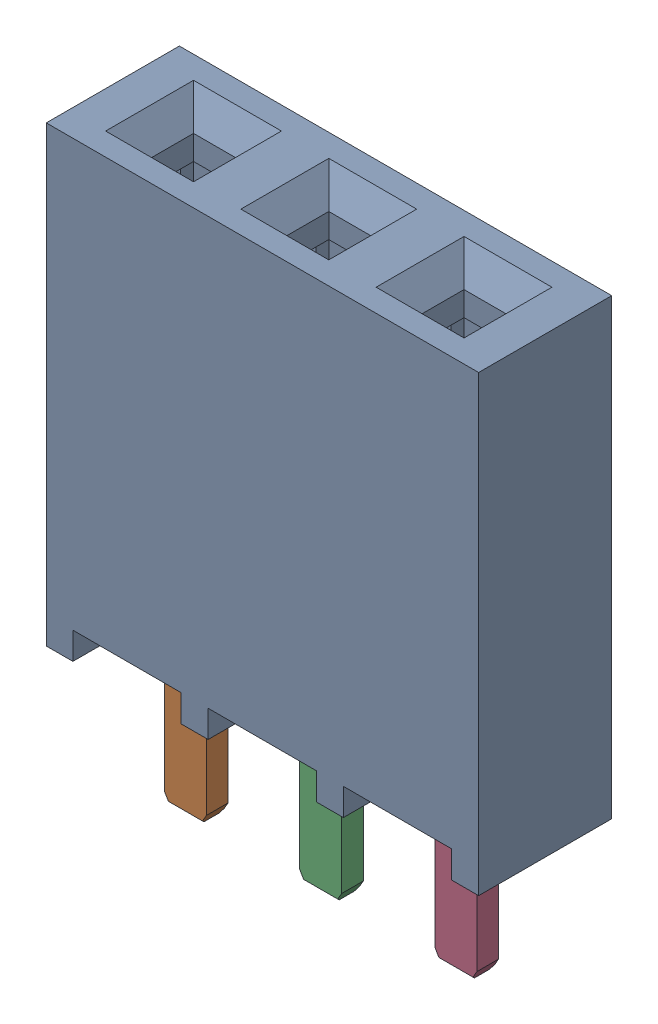
SolidWorks assembly L11-SSW-104-01-X-S_ASM, configuration Default. Lengths in mm.
Overall size (8.12 11.05 2.5).
4 component instances, 2 part files, 0 mates.
Components (placement in the parent):
- SSW-XX-X-1: SSW-XX-X [Default] at origin size (8.12 8.51 2.5)
- C-08-X-1: C-08-X [Default] at (-1.27 0.508 1.2192) size (1.96 9.53 0.41)
- C-08-X-2: C-08-X [Default] at (1.27 0.508 1.2192) size (1.96 9.53 0.41)
- C-08-X-3: C-08-X [Default] at (3.81 0.508 1.2192) size (1.96 9.53 0.41)
